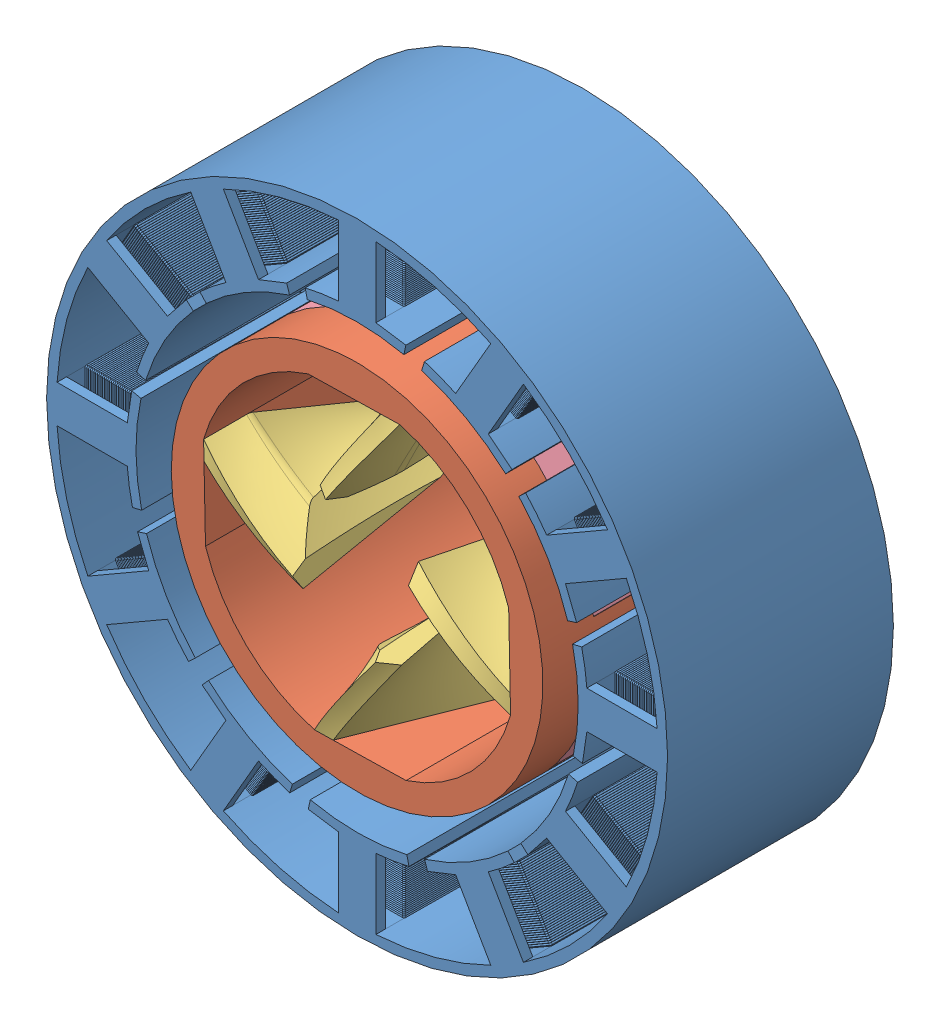
SolidWorks assembly propeller for robot, configuration Default. Lengths in mm.
Overall size (33 33 14.89).
21 component instances, 4 part files, 3 mates.
Components (placement in the parent):
- stator+wiring-1: stator+wiring [Default] at (30.7533 34.0912 42.0731) size (33 33 12)
- rotor propeller-1: rotor propeller [Default] at (20.6536 33.6207 65.0439) x (-0.039461 0.999221 0) z (0 0 1) size (19.75 19.77 14.89)
  - rotor-2: rotor [Default] at (0.0716 -10.1104 -20.1457) size (19.75 19.75 12)
  - propeller-8: propeller [Default] at (8.1814 -10.0261 -23.4423) x (0.01775 0.939531 -0.342002) z (-0.999822 0.01889 0) size (8.68 12.69 5)
  - propeller-9: propeller [Default] at (-0.0127 -2.0006 -23.4423) x (-0.939531 0.01775 -0.342002) z (-0.01889 -0.999822 0) size (8.68 12.69 5)
  - propeller-10: propeller [Default] at (-8.0381 -10.1948 -23.4423) x (-0.01775 -0.939531 -0.342002) z (0.999822 -0.01889 0) size (8.68 12.69 5)
  - propeller-11: propeller [Default] at (0.156 -18.2202 -23.4423) x (0.939531 -0.01775 -0.342002) z (0.01889 0.999822 0) size (8.68 12.69 5)
  - magnet NdFeB-15: magnet NdFeB [Default] at (-8.7817 -12.1311 -20.1457) x (-0.048662 0.998815 0) z (0 0 1) size (3.17 0.79 6.35)
  - magnet NdFeB-16: magnet NdFeB [Default] at (-7.0282 -15.7723 -20.1457) x (-0.477213 0.878788 0) z (0 0 1) size (3.17 0.79 6.35)
  - magnet NdFeB-17: magnet NdFeB [Default] at (-3.8685 -18.2921 -20.1457) x (-0.811245 0.584706 0) z (0 0 1) size (3.17 0.79 6.35)
  - magnet NdFeB-18: magnet NdFeB [Default] at (0.0716 -19.1914 -20.1457) x (-0.984601 0.174816 0) z (0 0 1) size (3.17 0.79 6.35)
  - magnet NdFeB-19: magnet NdFeB [Default] at (4.0117 -18.2921 -20.1457) x (-0.962945 -0.269699 0) z (0 0 1) size (3.17 0.79 6.35)
  - magnet NdFeB-20: magnet NdFeB [Default] at (7.1715 -15.7723 -20.1457) x (-0.750565 -0.660797 0) z (0 0 1) size (3.17 0.79 6.35)
  - magnet NdFeB-21: magnet NdFeB [Default] at (8.925 -12.1311 -20.1457) x (-0.389527 -0.921015 0) z (0 0 1) size (3.17 0.79 6.35)
  - magnet NdFeB-22: magnet NdFeB [Default] at (8.925 -8.0897 -20.1457) x (0.048662 -0.998815 0) z (0 0 1) size (3.17 0.79 6.35)
  - magnet NdFeB-23: magnet NdFeB [Default] at (7.1715 -4.4485 -20.1457) x (0.477213 -0.878788 0) z (0 0 1) size (3.17 0.79 6.35)
  - magnet NdFeB-24: magnet NdFeB [Default] at (4.0117 -1.9287 -20.1457) x (0.811245 -0.584706 0) z (0 0 1) size (3.17 0.79 6.35)
  - magnet NdFeB-25: magnet NdFeB [Default] at (0.0716 -1.0294 -20.1457) x (0.984601 -0.174816 0) z (0 0 1) size (3.17 0.79 6.35)
  - magnet NdFeB-26: magnet NdFeB [Default] at (-3.8685 -1.9287 -20.1457) x (0.962945 0.269699 0) z (0 0 1) size (3.17 0.79 6.35)
  - magnet NdFeB-27: magnet NdFeB [Default] at (-7.0282 -4.4485 -20.1457) x (0.750565 0.660797 0) z (0 0 1) size (3.17 0.79 6.35)
  - magnet NdFeB-28: magnet NdFeB [Default] at (-8.7817 -8.0897 -20.1457) x (0.389527 0.921015 0) z (0 0 1) size (3.17 0.79 6.35)
Mates (geometry in assembly coordinates):
- Coincident4: coincident aligned: plane of stator+wiring-1 through (30.7533 34.0912 42.0731) normal (0 0 -1); plane of rotor propeller-1/rotor-2 through (30.7533 34.0912 42.0731) normal (0 0 -1)
- Coincident5: coincident aligned: plane of stator+wiring-1 through (30.7533 34.0912 54.0731) normal (0 0 1); plane of rotor propeller-1/rotor-2 through (30.7533 34.0912 54.0731) normal (0 0 1)
- Concentric1: concentric aligned: cylinder of stator+wiring-1 through (30.7533 34.0912 54.0731) axis (0 0 -1) radius 16.5; cylinder of rotor propeller-1/rotor-2 through (30.7533 34.0912 51.2481) axis (0 0 -1) radius 9.875
